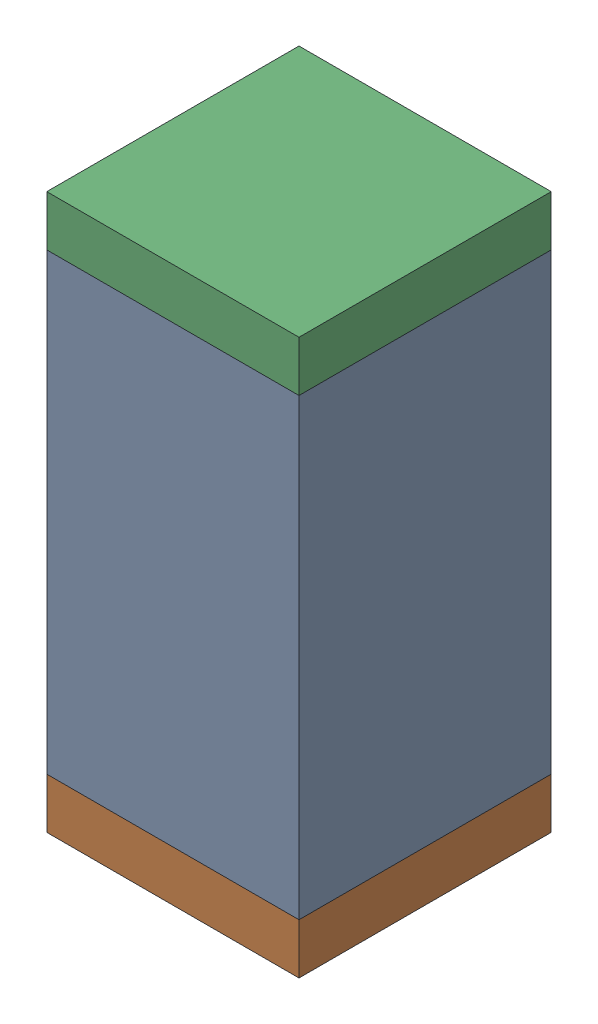
SolidWorks assembly C71, configuration Default. Lengths in mm.
Overall size (0.5 1.1 0.5).
6 component instances, 2 part files, 0 mates.
Components (placement in the parent):
- 791586336-1: 791586336 [Default] at (117.05 57.45 0) size (0.5 0.9 0.5)
  - Extruded_8-1: Extruded_8 [Default] at origin size (0.5 0.9 0.5)
- 810157360-1: 810157360 [Default] at (117.05 56.95 0) size (0.5 0.1 0.5)
  - Extruded_9-1: Extruded_9 [Default] at origin size (0.5 0.1 0.5)
- 810157360-2: 810157360 [Default] at (117.05 57.95 0) size (0.5 0.1 0.5)
  - Extruded_9-1: Extruded_9 [Default] at origin size (0.5 0.1 0.5)
